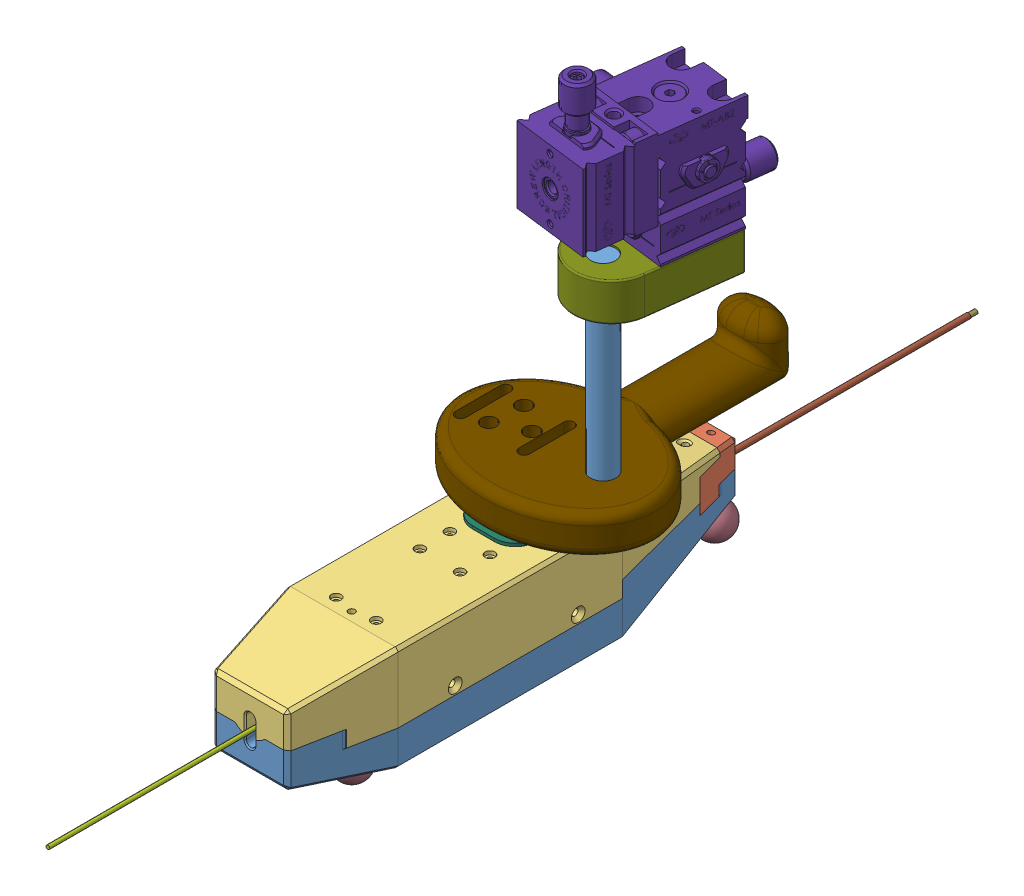
SolidWorks assembly FullAssembly, configuration Default. Lengths in mm.
Overall size (71.87 195.05 310).
39 component instances, 19 part files, 50 mates.
Components (placement in the parent):
- CasingAssembly-1: CasingAssembly [Default] at (63.6035 81.376 130.069) size (37 35 158)
  - Body2-1: Body2 [Default] at origin size (37 17.5 158)
  - Body1-2: Body1 [Default] at origin size (18.83 13.38 17)
  - Body3-1: Body3 [Default] at origin size (37 23 150)
- SLC-1770-S-NM-1: SLC-1770-S-NM [Default] at (66.2989 1.876 121.4347) x (-1 0 0) z (0 1 0) size (23 70 8)
  - SLC-1770-S-NM-1: SLC-1770-S-NM [Default] at (-5.8046 -26.3657 66) size (23 70 8)
  - Führung_1770_nm-1: Führung_1770_nm [Default] at (-1.3958 8.6343 71.3882) x (1 0 0) z (0 -1 0) size (17 4 70)
    - Schiene_1770-1: Schiene_1770 [Default] at (-4.4089 -1.3882 35) size (3.9 4 70)
    - Schiene_1770-2: Schiene_1770 [Default] at (12.5911 -1.3882 -35) x (-1 0 0) z (0 0 -1) size (3.9 4 70)
- SLC-1770-S-NM-2: SLC-1770-S-NM [Default] at (60.9081 160.876 121.4347) x (1 0 0) z (0 -1 0) size (23 70 8)
  - SLC-1770-S-NM-1: SLC-1770-S-NM [Default] at (-5.8046 -26.3657 66) size (23 70 8)
  - Führung_1770_nm-1: Führung_1770_nm [Default] at (-1.3958 8.6343 71.3882) x (1 0 0) z (0 -1 0) size (17 4 70)
    - Schiene_1770-1: Schiene_1770 [Default] at (-4.4089 -1.3882 35) size (3.9 4 70)
    - Schiene_1770-2: Schiene_1770 [Default] at (12.5911 -1.3882 -35) x (-1 0 0) z (0 0 -1) size (3.9 4 70)
- Schlitten_1770-1: Schlitten_1770 [Default] at (67.5035 72.376 142.069) x (-1 0 0) z (0 0 -1) size (7.8 4 70)
- Schlitten_1770-2: Schlitten_1770 [Default] at (67.5035 90.376 95.6837) x (-1 0 0) z (0 0 1) size (7.8 4 70)
- 1.27mmWire-2: 1.27mmWire [Default] at (63.6035 81.376 266.069) x (0 0 -1) z (-0.024578 0.999698 0) size (300 1.27 1.27)
- SmarAct Slide Assembly-1: SmarAct Slide Assembly [Default] at (42.2078 72.6072 91.3277) size (16 6.39 28)
  - SmarActSlideMount-1: SmarActSlideMount [Default] at (21.3957 3.7688 -4.2587) size (16 3 28)
  - tubeHolder-1: tubeHolder [Default] at (13.3957 6.7688 -10.2587) size (15.24 3.3 8)
  - BrassInsert-3: BrassInsert [Default] at (16.8957 3.7688 -14.2587) x (-0.555041 0 -0.831823) z (-0.831823 0 0.555041) size (3.58 3.11 3.58)
  - BrassInsert-4: BrassInsert [Default] at (25.8957 3.7688 -14.2587) x (-0.745433 0 -0.666581) z (-0.666581 0 0.745433) size (3.58 3.11 3.58)
- SmarAct Slide Assembly-2: SmarAct Slide Assembly [Default] at (42.2078 90.1448 146.425) x (1 0 0) z (0 0 -1) size (16 6.39 28)
  - SmarActSlideMount-1: SmarActSlideMount [Default] at (21.3957 3.7688 -4.2587) size (16 3 28)
  - tubeHolder-1: tubeHolder [Default] at (13.3957 6.7688 -10.2587) size (15.24 3.3 8)
  - BrassInsert-3: BrassInsert [Default] at (16.8957 3.7688 -14.2587) x (-0.555041 0 -0.831823) z (-0.831823 0 0.555041) size (3.58 3.11 3.58)
  - BrassInsert-4: BrassInsert [Default] at (25.8957 3.7688 -14.2587) x (-0.745433 0 -0.666581) z (-0.666581 0 0.745433) size (3.58 3.11 3.58)
- OuterTube-1: OuterTube [Default] at (63.6035 81.376 -41.431) x (0.936131 0.351651 0) z (0.351651 -0.936131 0) size (1.8 90 1.47)
- MiddleTube-1: MiddleTube [Default] at (63.6035 81.376 -43.931) x (-0.936131 -0.351651 0) z (-0.351651 0.936131 0) size (1.47 125 1.47)
- NDI_fiducial-1: NDI_fiducial [Default] at (63.6035 73.6187 44.757) x (-0.873916 0.082896 -0.478956) z (-0.486077 -0.149039 0.861113) size (11.5 14.52 11.5)
- NDI_fiducial-2: NDI_fiducial [Default] at (63.6035 64.8511 95.569) x (-0.837169 0 -0.546944) z (-0.546944 0 0.837169) size (11.5 14.52 11.5)
- NDI_fiducial-3: NDI_fiducial [Default] at (63.6035 64.5069 164.569) x (-0.837169 0 -0.546944) z (-0.546944 0 0.837169) size (11.5 14.52 11.5)
- Nano17-1: Nano17 [Default] at (63.6035 114.376 110.069) x (-1 0 0) z (0 0 1) size (17 14.5 23.38)
- ForceSensorAttachmentPlate-2: ForceSensorAttachmentPlate [Default] at (63.6035 97.876 110.069) x (0 0 1) z (-1 0 0) size (21 2.2 30.21)
- ForceSensorAttachmentPlate-3: ForceSensorAttachmentPlate [Default] at (63.6035 64.876 110.069) x (0 0 1) z (1 0 0) size (21 2.2 30.21)
- XYZ_stage_adapter-1: XYZ_stage_adapter [Default] at (95.5756 189.9233 90.2224) x (0.992331 0 0.123606) z (0.123606 0 -0.992331) size (25.4 12.7 42.9)
- stage_M-MT-XYZ-1: stage_M-MT-XYZ [Default] at (97.1454 189.9233 77.6197) x (-0.992331 0 -0.123606) z (0.123606 0 -0.992331) size (45.44 55.12 65.41)
- NanoMountPlatev2-1: NanoMountPlatev2 [Default] at (78.1035 114.376 110.069) x (0 0 1) z (0 1 0) size (99.35 69.89 80.87)
- mountArm-1: mountArm [Default] at (93.1035 189.376 110.069) x (-0.155827 0 -0.987784) z (0 -1 0) size (8.5 8.5 75)
Mates (geometry in assembly coordinates):
- Concentric1: concentric anti-aligned: circle of CasingAssembly-1/Body3-1; cylinder of SLC-1770-S-NM-2/SLC-1770-S-NM-1 through (70.3035 90.876 163.069) axis (0 -1 0) radius 0.625
- Concentric3: concentric anti-aligned: circle of CasingAssembly-1/Body3-1; cylinder of SLC-1770-S-NM-2/SLC-1770-S-NM-1 through (56.9035 90.876 97.069) axis (0 -1 0) radius 0.625
- Coincident1: coincident: line of CasingAssembly-1/Body3-1 through (51.1035 94.876 167.569) axis (0 0 -1); plane of SLC-1770-S-NM-2/SLC-1770-S-NM-1 through (55.1035 94.876 165.069) normal (0 1 0)
- Concentric5: concentric anti-aligned: cylinder of CasingAssembly-1/Body2-1 through (56.9035 63.876 97.069) axis (0 -1 0) radius 0.85; cylinder of SLC-1770-S-NM-1/SLC-1770-S-NM-1 through (56.9035 71.876 97.069) axis (0 1 0) radius 0.625
- Concentric6: concentric anti-aligned: cylinder of CasingAssembly-1/Body2-1 through (56.9035 63.876 163.069) axis (0 -1 0) radius 0.85; cylinder of SLC-1770-S-NM-1/SLC-1770-S-NM-1 through (56.9035 71.876 163.069) axis (0 1 0) radius 0.625
- Coincident2: coincident anti-aligned: plane of CasingAssembly-1/Body2-1 through (51.1035 67.876 167.569) normal (0 1 0); plane of SLC-1770-S-NM-1/SLC-1770-S-NM-1 through (72.1035 67.876 165.069) normal (0 -1 0)
- Distance1: distance = 0.7 mm anti-aligned: plane of Schlitten_1770-1 through (59.7035 74.586 72.069) normal (-1 0 0); plane of SLC-1770-S-NM-1/Führung_1770_nm-1/Schiene_1770-2 through (59.0035 75.876 95.069) normal (1 0 0)
- Parallel4: parallel aligned: plane of SLC-1770-S-NM-1/Führung_1770_nm-1/Schiene_1770-1 through (72.1035 75.876 165.069) normal (0 1 0); plane of Schlitten_1770-1 through (67.5035 76.376 72.069) normal (0 1 0)
- Distance3: distance = 0.5 mm anti-aligned: plane of Schlitten_1770-1 through (67.5035 72.376 72.069) normal (0 -1 0); plane of SLC-1770-S-NM-1/SLC-1770-S-NM-1 through (72.1035 71.876 165.069) normal (0 1 0)
- LimitDistance1: limit distance = -23 mm aligned: plane of Schlitten_1770-1 through (67.5035 72.376 72.069) normal (0 0 -1); plane of SLC-1770-S-NM-1/SLC-1770-S-NM-1 through (72.1035 71.876 95.069) normal (0 0 -1)
- Distance5: distance = 0.7 mm anti-aligned: plane of Schlitten_1770-2 through (67.5035 88.166 165.6837) normal (1 0 0); plane of SLC-1770-S-NM-2/Führung_1770_nm-1/Schiene_1770-2 through (68.2035 86.876 95.069) normal (-1 0 0)
- Parallel5: parallel anti-aligned: plane of SLC-1770-S-NM-2/Führung_1770_nm-1/Schiene_1770-1 through (59.0035 86.876 165.069) normal (1 0 0); plane of Schlitten_1770-2 through (59.7035 88.166 165.6837) normal (-1 0 0)
- Distance6: distance = 0.5 mm anti-aligned: plane of Schlitten_1770-2 through (67.5035 90.376 165.6837) normal (0 1 0); plane of SLC-1770-S-NM-2/SLC-1770-S-NM-1 through (55.1035 90.876 165.069) normal (0 -1 0)
- LimitDistance2: limit distance = -0.6147 mm aligned: plane of Schlitten_1770-2 through (67.5035 90.376 165.6837) normal (0 0 1); plane of SLC-1770-S-NM-2/SLC-1770-S-NM-1 through (55.1035 90.876 165.069) normal (0 0 1)
- Concentric7: concentric anti-aligned: cylinder of CasingAssembly-1/Body1-2 through (63.6035 81.376 45.6146) axis (0 0 -1) radius 0.9; cylinder of 1.27mmWire-2 through (63.6035 81.376 -33.931) axis (0 0 1) radius 0.635
- Concentric8: concentric anti-aligned: cylinder of Schlitten_1770-1 through (63.6035 72.376 77.069) axis (0 -1 0) radius 0.825; cylinder of SmarAct Slide Assembly-1/SmarActSlideMount-1 through (63.6035 79.376 77.069) axis (0 1 0) radius 0.85
- Concentric9: concentric anti-aligned: cylinder of Schlitten_1770-1 through (63.6035 72.376 87.069) axis (0 -1 0) radius 0.825; cylinder of SmarAct Slide Assembly-1/SmarActSlideMount-1 through (63.6035 79.376 87.069) axis (0 1 0) radius 0.85
- Coincident3: coincident anti-aligned: plane of Schlitten_1770-1 through (67.5035 76.376 72.069) normal (0 1 0); plane of SmarAct Slide Assembly-1/SmarActSlideMount-1 through (63.6035 76.376 87.069) normal (0 -1 0)
- Concentric10: concentric anti-aligned: cylinder of Schlitten_1770-2 through (63.6035 90.376 160.6837) axis (0 1 0) radius 0.825; cylinder of SmarAct Slide Assembly-2/SmarActSlideMount-1 through (63.6035 83.376 160.6837) axis (0 -1 0) radius 0.85
- Concentric11: concentric anti-aligned: cylinder of Schlitten_1770-2 through (63.6035 90.376 150.6837) axis (0 1 0) radius 0.825; cylinder of SmarAct Slide Assembly-2/SmarActSlideMount-1 through (63.6035 83.376 150.6837) axis (0 -1 0) radius 0.85
- Coincident5: coincident anti-aligned: plane of Schlitten_1770-2 through (67.5035 86.376 165.6837) normal (0 -1 0); plane of SmarAct Slide Assembly-2/SmarActSlideMount-1 through (63.6035 86.376 150.6837) normal (0 1 0)
- Coincident7: coincident aligned: plane of CasingAssembly-1/Body1-2 through (63.6035 81.376 48.569) normal (0 0 1); circle of OuterTube-1
- Parallel9: parallel aligned: plane of OuterTube-1 through (63.2653 80.2858 -41.431) normal (0.936131 0.351651 0); plane of MiddleTube-1 through (63.394 80.5118 -33.931) normal (0.936131 0.351651 0)
- LimitDistance5: limit distance = 0 mm aligned: plane of MiddleTube-1 through (63.6035 81.376 -33.931) normal (0 0 -1); plane of 1.27mmWire-2 through (63.6035 81.376 -33.931) normal (0 0 -1)
- Coincident11: coincident aligned: plane of SmarAct Slide Assembly-1/tubeHolder-1 through (55.6035 81.876 81.069) normal (0 0 1); plane of MiddleTube-1 through (63.6035 81.376 81.069) normal (0 0 1)
- Concentric22: concentric anti-aligned: cylinder of CasingAssembly-1/Body2-1 through (63.6035 77.6794 45.4598) axis (0 -0.985351 -0.170541) radius 1.1; cylinder of NDI_fiducial-1 through (63.6035 73.6187 44.757) axis (0 0.985351 0.170541) radius 2.795
- Concentric23: concentric anti-aligned: cylinder of CasingAssembly-1/Body2-1 through (63.6035 97.9873 95.569) axis (0 -1 0) radius 1.1; cylinder of NDI_fiducial-2 through (63.6035 64.8511 95.569) axis (0 1 0) radius 2.795
- Concentric24: concentric anti-aligned: cylinder of CasingAssembly-1/Body2-1 through (63.6035 97.9873 164.569) axis (0 -1 0) radius 1.1; cylinder of NDI_fiducial-3 through (63.6035 64.5069 164.569) axis (0 1 0) radius 2.795
- Concentric30: concentric aligned: cylinder of Nano17-1 through (58.1908 99.876 106.944) axis (0 -1 0) radius 1; cylinder of ForceSensorAttachmentPlate-2 through (58.1908 97.876 106.944) axis (0 -1 0) radius 1.1
- Concentric31: concentric aligned: cylinder of Nano17-1 through (69.0162 99.876 106.944) axis (0 -1 0) radius 1; cylinder of ForceSensorAttachmentPlate-2 through (69.0162 97.876 106.944) axis (0 -1 0) radius 1.1
- Coincident14: coincident anti-aligned: plane of Nano17-1 through (63.6035 99.876 110.069) normal (0 -1 0); plane of ForceSensorAttachmentPlate-2 through (63.6035 99.876 110.069) normal (0 1 0)
- Coincident17: coincident anti-aligned: plane of CasingAssembly-1/Body3-1 through (63.6035 97.876 110.069) normal (0 1 0); plane of ForceSensorAttachmentPlate-2 through (63.6035 97.876 110.069) normal (0 -1 0)
- Concentric36: concentric aligned: circle of CasingAssembly-1/Body1-2; cylinder of OuterTube-1 through (63.6035 81.376 48.569) axis (0 0 -1) radius 0.9017
- Concentric38: concentric anti-aligned: cylinder of 1.27mmWire-2 through (63.6035 81.376 -33.931) axis (0 0 1) radius 0.635; cylinder of OuterTube-1 through (63.6035 81.376 48.569) axis (0 0 -1) radius 0.9017
- Concentric41: concentric aligned: cylinder of SmarAct Slide Assembly-2/tubeHolder-1 through (63.6035 81.376 164.6837) axis (0 0 -1) radius 0.78; cylinder of MiddleTube-1 through (63.6035 81.376 81.069) axis (0 0 -1) radius 0.7353
- Concentric49: concentric aligned: circle of CasingAssembly-1/Body3-1; cylinder of ForceSensorAttachmentPlate-2 through (52.9993 99.876 110.069) axis (0 1 0) radius 1.1
- Concentric50: concentric aligned: circle of CasingAssembly-1/Body3-1; cylinder of ForceSensorAttachmentPlate-2 through (74.2077 99.876 110.069) axis (0 1 0) radius 1.1
- Concentric54: concentric aligned: cone of CasingAssembly-1/Body2-1 through (74.2077 67.876 110.069) axis (0 -1 0); cylinder of ForceSensorAttachmentPlate-3 through (74.2077 62.876 110.069) axis (0 -1 0) radius 1.1
- Concentric55: concentric aligned: cone of CasingAssembly-1/Body2-1 through (52.9993 67.876 110.069) axis (0 -1 0); cylinder of ForceSensorAttachmentPlate-3 through (52.9993 62.876 110.069) axis (0 -1 0) radius 1.1
- Coincident22: coincident anti-aligned: plane of CasingAssembly-1/Body2-1 through (82.1035 63.876 41.6377) normal (0 -1 0); plane of ForceSensorAttachmentPlate-3 through (63.6035 63.876 110.069) normal (0 1 0)
- Concentric63: concentric aligned: cylinder of XYZ_stage_adapter-1 through (94.3198 191.9233 100.3044) axis (0 -1 0) radius 0.9; cylinder of stage_M-MT-XYZ-1 through (94.3198 189.9233 100.3044) axis (0 -1 0) radius 0.8001
- Concentric64: concentric aligned: cylinder of XYZ_stage_adapter-1 through (96.8315 191.9233 80.1403) axis (0 -1 0) radius 0.9; cylinder of stage_M-MT-XYZ-1 through (96.8315 189.9233 80.1403) axis (0 -1 0) radius 0.8001
- Concentric65: concentric anti-aligned: cylinder of XYZ_stage_adapter-1 through (95.5756 182.0837 90.2224) axis (0 -1 0) radius 3.75; cylinder of stage_M-MT-XYZ-1 through (95.5756 194.4191 90.2224) axis (0 1 0) radius 1.7272
- Coincident32: coincident anti-aligned: plane of XYZ_stage_adapter-1 through (95.5756 189.9233 90.2224) normal (0 1 0); plane of stage_M-MT-XYZ-1 through (106.6084 189.9233 104.3948) normal (0 -1 0)
- Concentric66: concentric anti-aligned: cylinder of Nano17-1 through (69.8297 114.376 110.6137) axis (0 1 0) radius 1; cylinder of NanoMountPlatev2-1 through (69.8297 135.731 110.6137) axis (0 -1 0) radius 2.5
- Concentric67: concentric anti-aligned: cylinder of XYZ_stage_adapter-1 through (93.1035 177.2233 110.069) axis (0 1 0) radius 4.125; cylinder of NanoMountPlatev2-1 through (93.1035 127.076 110.069) axis (0 -1 0) radius 4.25
- Concentric68: concentric aligned: cylinder of Nano17-1 through (60.0187 114.376 115.1887) axis (0 1 0) radius 1; cylinder of NanoMountPlatev2-1 through (60.0187 114.376 115.1887) axis (0 1 0) radius 1.15
- Concentric69: concentric anti-aligned: cylinder of NanoMountPlatev2-1 through (93.1035 127.076 110.069) axis (0 -1 0) radius 4.25; cylinder of mountArm-1 through (93.1035 114.376 110.069) axis (0 1 0) radius 4.25
- Coincident33: coincident aligned: plane of NanoMountPlatev2-1 through (78.1035 114.376 110.069) normal (0 -1 0); plane of mountArm-1 through (93.1035 114.376 110.069) normal (0 -1 0)
- Coincident34: coincident anti-aligned: plane of Nano17-1 through (55.1035 114.376 110.069) normal (0 1 0); plane of NanoMountPlatev2-1 through (78.1035 114.376 110.069) normal (0 -1 0)
